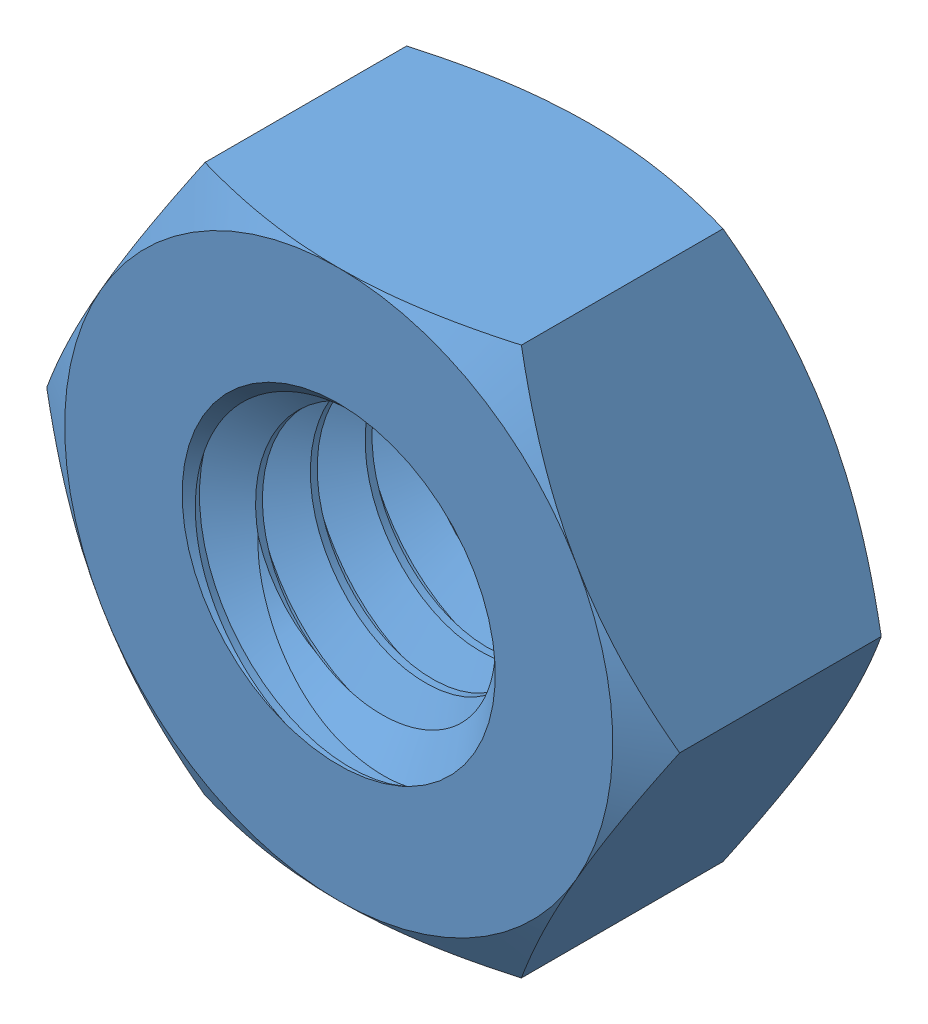
SolidWorks assembly embeddableNut, configuration Default. Lengths in mm.
Overall size (8.08 7 3.75).
3 component instances, 3 part files, 3 mates.
Components (placement in the parent):
- nut^embeddableNut-1: nut^embeddableNut [Default] at origin size (8.08 7 3.75) (virtual)
- nutCave^embeddableNut-1: nutCave^embeddableNut [Default] at origin size (35 7.8 4.2) (hidden, virtual)
- embedmentCylinder^embeddableNut-1: embedmentCylinder^embeddableNut [Default] at origin size (14 14 8.96) (hidden, virtual)
Mates (geometry in assembly coordinates):
- Coincident2: coordinate: point of ?
- Coincident3: coordinate: unknown of ?
- Coincident4: coordinate: unknown of ?
